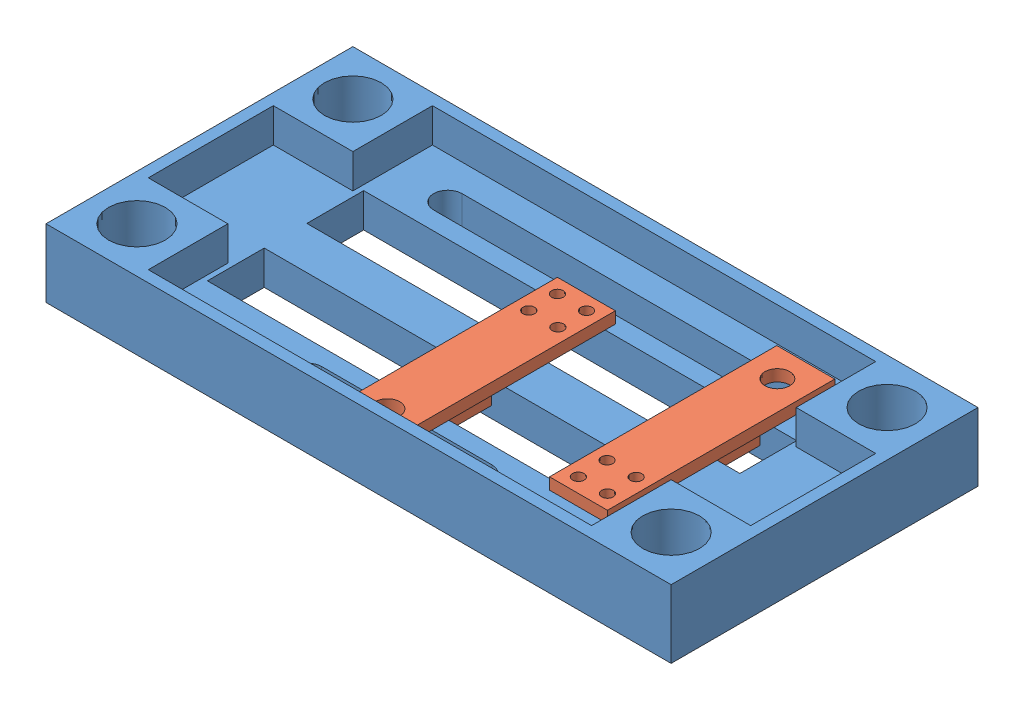
SolidWorks assembly reflect_assem, configuration Default. Lengths in mm.
Overall size (55 6 27).
3 component instances, 2 part files, 8 mates.
Components (placement in the parent):
- reflectance_holder-1: reflectance_holder [Default] at origin size (55 6 27)
- Reflectance_Sensor-2: Reflectance_Sensor [Default] at (14.5 3 -1.35) size (5.1 2.52 20)
- Reflectance_Sensor-3: Reflectance_Sensor [Default] at (-0.3542 3 3.1) x (-1 0 0) z (0 0 -1) size (5.1 2.52 20)
Mates (geometry in assembly coordinates):
- Coincident1: coincident aligned: plane of reflectance_holder-1 through (0 0 0) normal (0 0 1)
- Coincident2: coincident aligned: plane of reflectance_holder-1 through (0 0 0) normal (0 1 0)
- Coincident3: coincident aligned: plane of reflectance_holder-1 through (0 0 0) normal (1 0 0)
- Coincident5: coincident anti-aligned: plane of reflectance_holder-1 through (0 3 0) normal (0 1 0); plane of Reflectance_Sensor-2 through (14.5 3 -1.35) normal (0 -1 0)
- Width2: width anti-aligned: plane of Reflectance_Sensor-2 through (12.6975 1.5 -5.5) normal (0 0 -1); plane of Reflectance_Sensor-2 through (12.6975 1.5 -1.5) normal (0 0 1); plane of reflectance_holder-1 through (-19.05 3 -6) normal (0 0 1); plane of reflectance_holder-1 through (-19.05 3 -1) normal (0 0 -1)
- Concentric1: concentric anti-aligned: cylinder of reflectance_holder-1 through (14.5 0 -8.85) axis (0 1 0) radius 1.25; cylinder of Reflectance_Sensor-2 through (14.5 4.02 -8.85) axis (0 -1 0) radius 1.09
- Coincident6: coincident anti-aligned: plane of reflectance_holder-1 through (0 3 0) normal (0 1 0); plane of Reflectance_Sensor-3 through (-0.3542 3 3.1) normal (0 -1 0)
- Width3: width aligned: plane of Reflectance_Sensor-3 through (1.4483 1.5 7.25) normal (0 0 1); plane of Reflectance_Sensor-3 through (1.4483 1.5 3.25) normal (0 0 -1); plane of reflectance_holder-1 through (-19.05 3 2.75) normal (0 0 1); plane of reflectance_holder-1 through (-19.05 3 7.75) normal (0 0 -1)
